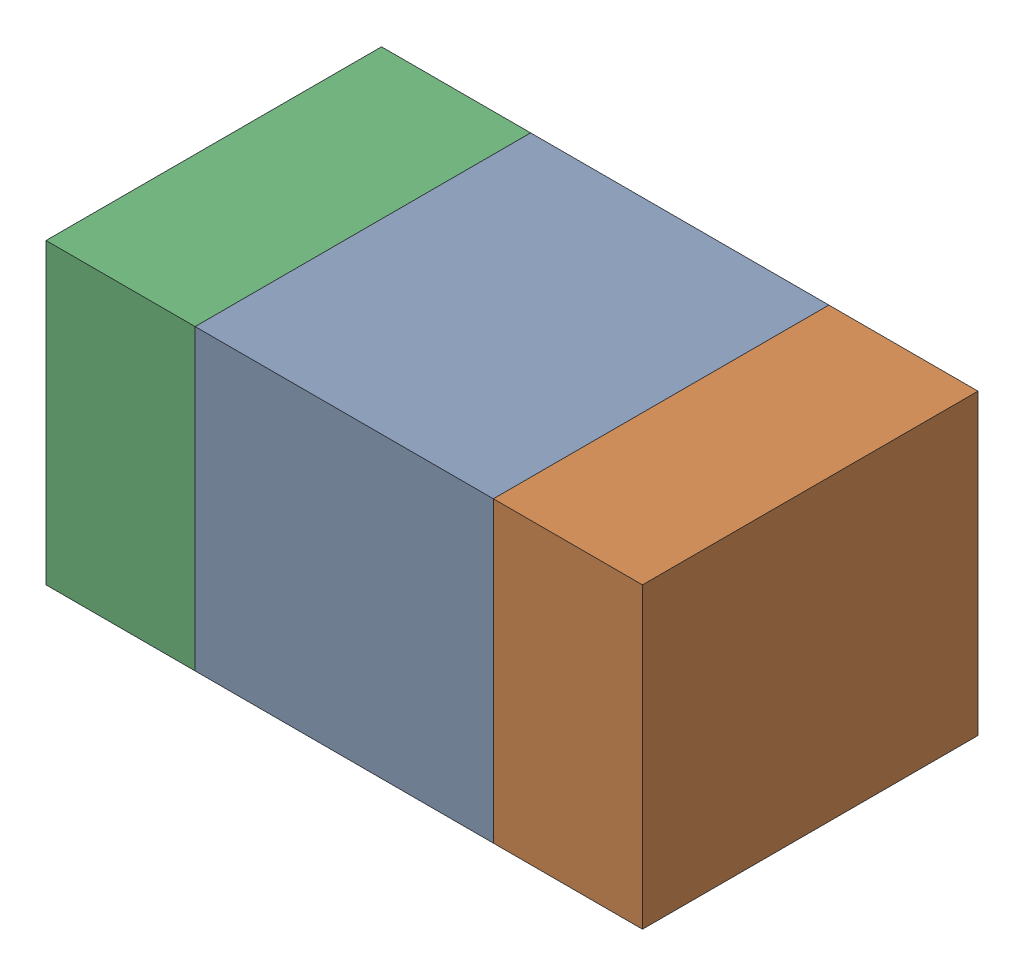
SolidWorks assembly C2, configuration ﾃﾞﾌｫﾙﾄ. Lengths in mm.
Overall size (1.6 0.8 0.9).
6 component instances, 2 part files, 0 mates.
Components (placement in the parent):
- 689259608-1: 689259608 [ﾃﾞﾌｫﾙﾄ] at (21.5 31.2501 0) size (0.8 0.8 0.9)
  - Extruded_3-1: Extruded_3 [ﾃﾞﾌｫﾙﾄ] at origin size (0.8 0.8 0.9)
- 689259744-1: 689259744 [ﾃﾞﾌｫﾙﾄ] at (22.1001 31.2501 0) size (0.4 0.8 0.9)
  - Extruded_4-1: Extruded_4 [ﾃﾞﾌｫﾙﾄ] at origin size (0.4 0.8 0.9)
- 689259744-2: 689259744 [ﾃﾞﾌｫﾙﾄ] at (20.9001 31.2501 0) size (0.4 0.8 0.9)
  - Extruded_4-1: Extruded_4 [ﾃﾞﾌｫﾙﾄ] at origin size (0.4 0.8 0.9)
